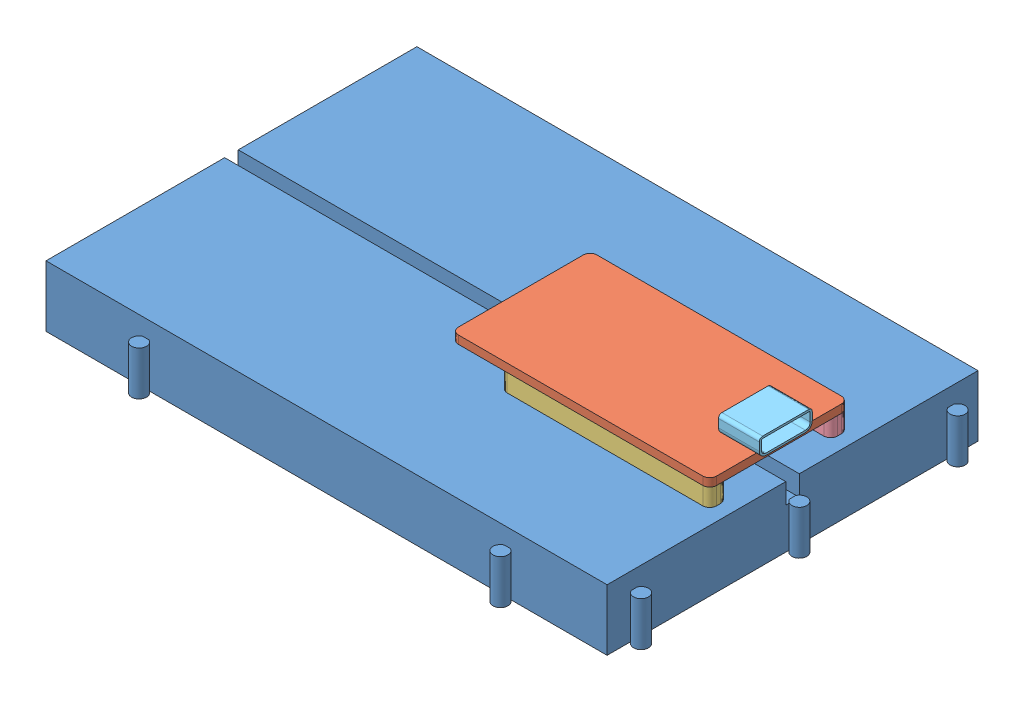
SolidWorks assembly redbear_breadboard_assy, configuration Default. Lengths in mm.
Overall size (84.7 15.5 56.7).
6 component instances, 5 part files, 3 mates.
Components (placement in the parent):
- Breadboard2-1: Breadboard2 [Default] at origin size (84.7 9 56.7)
- redbear_duo_assy-1: redbear_duo_assy [Default] at (-40.8953 9.736 46.697) x (0 0 -1) z (1 0 0) size (20.4 6.5 39)
  - Component1-1: Component1 [Default] at (19.197 -0.736 15.8953) size (20.4 1.2 38)
  - Component2-1: Component2 [Default] at (19.197 3.264 15.8953) size (2.6 2.6 30.8)
  - Component3-1: Component3 [Default] at (19.197 -0.736 15.8953) size (2.6 2.6 30.8)
  - Component4-1: Component4 [Default] at (19.197 -0.736 15.1953) size (7.8 2.7 6)
Mates (geometry in assembly coordinates):
- Coincident2: coincident anti-aligned: plane of Breadboard2-1 through (0 9 0) normal (0 1 0); plane of redbear_duo_assy-1/Component3-1 through (-1.99 9 17.09) normal (0 -1 0)
- Distance2: distance = 9.2 mm anti-aligned: plane of redbear_duo_assy-1/Component3-1 through (-2.99 8.99 17.1) normal (0 0 -1); plane of Breadboard2-1 through (0 9 26.3) normal (0 0 1)
- Distance3: distance = 1 mm aligned: plane of Breadboard2-1 through (0 6 27.7583) normal (1 0 0); plane of redbear_duo_assy-1/Component4-1 through (-1 12.79 31.21) normal (1 0 0)
